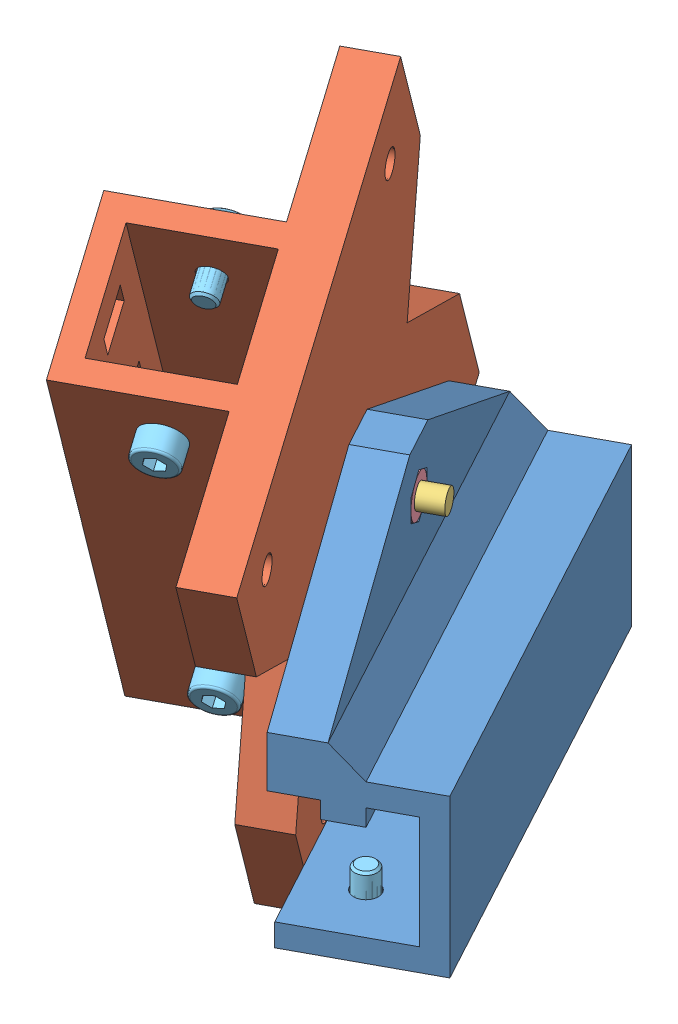
SolidWorks assembly hinge, configuration SymétrieDéfaut. Lengths in mm.
17 component instances, 6 part files, 71 mates.
Components (placement in the parent):
- FoldarapM_hinge-inner_2off-1: FoldarapM_hinge-inner_2off [SymétrieDéfaut] at (2.8366 41.2656 -46.9992) x (0.475399 0 0.87977) z (-0.87977 0 0.475399) size (80 53 24)
- FoldarapM_hinge-outer_2off-1: FoldarapM_hinge-outer_2off [SymétrieDéfaut] at (-8.7977 44 4.754) x (0.428728 -0.432097 0.793401) z (-0.87977 0 0.475399) size (80 80 32)
- Aluminium Profile with 6mm Slot 400mm-1: Aluminium Profile with 6mm Slot 400mm [SymétrieDefault] at (45.704 374.9337 137.2278) x (-0.428728 0.432097 -0.793401) z (-0.205419 -0.901827 -0.380146) size (20 20 400)
- slotted cheese head screw_din-1: slotted cheese head screw_din [PreviewCfg] at (-14.6042 44 7.8916) x (0.87977 0 -0.475399) z (-0.475399 0 -0.87977) size (18.61 7 7)
- hex nut style 1 gradeab_din-1: hex nut style 1 gradeab_din [PreviewCfg] at (-4.5748 44 2.4721) x (-0.475399 0 -0.87977) z (-0.87977 0 0.475399) size (8 9.24 4.7)
- socket head cap screw_din2-1: socket head cap screw_din2 [DIN 912 M4 x 8 --- 8C] at (14.262 -4 26.3931) x (0 1 0) z (0.546944 0 -0.837169) size (12 7 7)
- socket head cap screw_din2-2: socket head cap screw_din2 [DIN 912 M4 x 8 --- 8C] at (0 -4 0) x (0 1 0) z (0.546944 0 -0.837169) size (12 7 7)
- socket head cap screw_din2-3: socket head cap screw_din2 [DIN 912 M4 x 8 --- 8C] at (-14.262 -4 -26.3931) x (0 1 0) z (0.546944 0 -0.837169) size (12 7 7)
- socket head cap screw_din2-4: socket head cap screw_din2 [DIN 912 M4 x 8 --- 8C] at (-46.632 16.9452 10.464) x (0.87977 0 -0.475399) z (0.475399 0 0.87977) size (12 7 7)
- socket head cap screw_din2-5: socket head cap screw_din2 [DIN 912 M4 x 8 --- 8C] at (-26.1881 78.8326 10.4344) x (0.428728 -0.432097 0.793401) z (-0.812844 0.198803 0.547505) size (12 7 7)
- socket head cap screw_din2-6: socket head cap screw_din2 [DIN 912 M4 x 8 --- 8C] at (-38.5132 24.7229 -12.3744) x (0.428728 -0.432097 0.793401) z (-0.812844 0.198803 0.547505) size (12 7 7)
- socket head cap screw_din2-7: socket head cap screw_din2 [DIN 912 M4 x 8 --- 8C] at (-23.079 9.1674 16.188) x (-0.428728 0.432097 -0.793401) z (-0.812844 0.198803 0.547505) size (12 7 7)
- socket head cap screw_din2-8: socket head cap screw_din2 [DIN 912 M4 x 8 --- 8C] at (-10.7539 63.2771 38.9968) x (-0.428728 0.432097 -0.793401) z (-0.812844 0.198803 0.547505) size (12 7 7)
- socket head cap screw_din2-9: socket head cap screw_din2 [DIN 912 M4 x 8 --- 8N] at (-26.0542 84.0177 -1.9388) x (0.87977 0 -0.475399) z (0.475399 0 0.87977) size (12 7 7)
- socket head cap screw_din2-10: socket head cap screw_din2 [DIN 912 M4 x 8 --- 8N] at (-38.3793 29.9081 -24.7476) x (0.87977 0 -0.475399) z (0.475399 0 0.87977) size (12 7 7)
- socket head cap screw_din2-11: socket head cap screw_din2 [DIN 912 M4 x 8 --- 8N] at (-12.6557 3.9823 22.8564) x (0.87977 0 -0.475399) z (0.475399 0 0.87977) size (12 7 7)
- socket head cap screw_din2-12: socket head cap screw_din2 [DIN 912 M4 x 8 --- 8N] at (-0.3305 58.0919 45.6652) x (0.87977 0 -0.475399) z (0.475399 0 0.87977) size (12 7 7)
Mates (geometry in assembly coordinates):
- Coaxiale1: concentric aligned: cylinder of FoldarapM_hinge-inner_2off-1 through (-1.7595 44 0.9508) axis (0.87977 0 -0.475399) radius 2.25; cylinder of FoldarapM_hinge-outer_2off-1 through (-8.7977 44 4.754) axis (0.87977 0 -0.475399) radius 2.2
- Coïncidente1: coincident anti-aligned: plane of FoldarapM_hinge-inner_2off-1 through (10.2183 24 39.9448) normal (-0.87977 0 0.475399); plane of FoldarapM_hinge-outer_2off-1 through (-8.7977 44 4.754) normal (0.87977 0 -0.475399)
- Coaxiale2: concentric anti-aligned: cylinder of FoldarapM_hinge-outer_2off-1 through (-8.7977 44 4.754) axis (0.87977 0 -0.475399) radius 2.2; cylinder of slotted cheese head screw_din-1 through (-36.9503 44 19.9668) axis (-0.87977 0 0.475399) radius 2
- Coïncidente2: coincident anti-aligned: plane of FoldarapM_hinge-outer_2off-1 through (-12.3168 44 6.6556) normal (-0.87977 0 0.475399); plane of slotted cheese head screw_din-1 through (-12.3168 42 6.6556) normal (0.87977 0 -0.475399)
- Coaxiale3: concentric aligned: cylinder of slotted cheese head screw_din-1 through (-36.9503 44 19.9668) axis (-0.87977 0 0.475399) radius 2; cylinder of hex nut style 1 gradeab_din-1 through (17.4524 44 -9.4307) axis (-0.87977 0 0.475399) radius 2
- Coïncidente3: coincident aligned: plane of FoldarapM_hinge-outer_2off-1; plane of Aluminium Profile with 6mm Slot 400mm-1
- Coïncidente4: coincident anti-aligned: plane of FoldarapM_hinge-outer_2off-1 through (-31.6289 2.9436 21.4006) normal (0.87977 0 -0.475399); plane of Aluminium Profile with 6mm Slot 400mm-1 through (-25.7345 7.2886 32.3087) normal (-0.87977 0 0.475399)
- Coïncidente5: coincident anti-aligned: plane of FoldarapM_hinge-outer_2off-1; plane of Aluminium Profile with 6mm Slot 400mm-1
- Coïncidente6: coincident aligned: plane of FoldarapM_hinge-inner_2off-1 through (17.2564 53 36.1416) normal (0.87977 0 -0.475399); plane of hex nut style 1 gradeab_din-1 through (-1.7595 39.9585 0.9508) normal (0.87977 0 -0.475399)
- Parallèle1: parallel anti-aligned: plane of FoldarapM_hinge-inner_2off-1 through (31.3328 0 28.5352) normal (0 -1 0); plane of assembly through (0 0 0) normal (0 1 0)
- Coïncidente8: coincident: line of FoldarapM_hinge-inner_2off-1 through (19.016 0 35.1908) axis (-0.475399 0 -0.87977); point of assembly
- Coïncidente9: coincident: line of FoldarapM_hinge-inner_2off-1 through (-7.9179 0 4.2786) axis (0.87977 0 -0.475399); point of assembly
- Coaxiale4: concentric aligned: cylinder of FoldarapM_hinge-inner_2off-1 through (14.262 0 26.3931) axis (0 -1 0) radius 2.2; cylinder of socket head cap screw_din2-1 through (14.262 -35.75 26.3931) axis (0 -1 0) radius 3.5
- Coïncidente10: coincident anti-aligned: plane of FoldarapM_hinge-inner_2off-1 through (31.3328 0 28.5352) normal (0 -1 0); plane of socket head cap screw_din2-1 through (17.1921 0 28.3074) normal (0 1 0)
- Coaxiale5: concentric aligned: cylinder of FoldarapM_hinge-inner_2off-1 through (0 0 0) axis (0 -1 0) radius 2.2; cylinder of socket head cap screw_din2-2 through (0 -35.75 0) axis (0 -1 0) radius 3.5
- Coïncidente11: coincident anti-aligned: plane of FoldarapM_hinge-inner_2off-1 through (31.3328 0 28.5352) normal (0 -1 0); plane of socket head cap screw_din2-2 through (2.9301 0 1.9143) normal (0 1 0)
- Coaxiale6: concentric aligned: cylinder of FoldarapM_hinge-inner_2off-1 through (-14.262 0 -26.3931) axis (0 -1 0) radius 2.2; cylinder of socket head cap screw_din2-3 through (-14.262 -35.75 -26.3931) axis (0 -1 0) radius 3.5
- Coïncidente12: coincident anti-aligned: plane of FoldarapM_hinge-inner_2off-1 through (31.3328 0 28.5352) normal (0 -1 0); plane of socket head cap screw_din2-3 through (-11.3319 0 -24.4788) normal (0 1 0)
- Coaxiale7: concentric aligned: cylinder of FoldarapM_hinge-outer_2off-1 through (-32.2337 15.6881 28.6954) axis (-0.87977 0 0.475399) radius 2.2; cylinder of socket head cap screw_din2-4 through (-63.6855 15.6881 45.6909) axis (-0.87977 0 0.475399) radius 3.5
- Coïncidente13: coincident anti-aligned: plane of FoldarapM_hinge-outer_2off-1 through (-36.9426 1.6208 19.9812) normal (-0.87977 0 0.475399); plane of socket head cap screw_din2-4 through (-32.2337 19.1881 28.6954) normal (0.87977 0 -0.475399)
- Coaxiale8: concentric anti-aligned: cylinder of FoldarapM_hinge-outer_2off-1 through (-23.0691 76.9419 16.2063) axis (0.448649 0.330715 0.830266) radius 2.2; cylinder of socket head cap screw_din2-5 through (-51.6705 55.8589 -36.7231) axis (-0.448649 -0.330715 -0.830266) radius 3.5
- Coïncidente14: coincident anti-aligned: plane of FoldarapM_hinge-outer_2off-1; plane of socket head cap screw_din2-5
- Coaxiale9: concentric anti-aligned: cylinder of FoldarapM_hinge-outer_2off-1 through (-13.6358 20.3181 33.6635) axis (0.448649 0.330715 0.830266) radius 2.2; cylinder of socket head cap screw_din2-6 through (-42.2372 -0.765 -19.266) axis (-0.448649 -0.330715 -0.830266) radius 3.5
- Coïncidente15: coincident anti-aligned: plane of FoldarapM_hinge-outer_2off-1; plane of socket head cap screw_din2-6
- Coaxiale10: concentric aligned: cylinder of FoldarapM_hinge-outer_2off-1 through (-13.6358 20.3181 33.6635) axis (0.448649 0.330715 0.830266) radius 2.2; cylinder of socket head cap screw_din2-7 through (2.4034 32.1411 63.3455) axis (0.448649 0.330715 0.830266) radius 3.5
- Coïncidente16: coincident anti-aligned: plane of FoldarapM_hinge-outer_2off-1; plane of socket head cap screw_din2-7
- Coaxiale11: concentric aligned: cylinder of FoldarapM_hinge-outer_2off-1 through (-23.0691 76.9419 16.2063) axis (0.448649 0.330715 0.830266) radius 2.2; cylinder of socket head cap screw_din2-8 through (-7.0299 88.765 45.8883) axis (0.448649 0.330715 0.830266) radius 3.5
- Coïncidente17: coincident anti-aligned: plane of FoldarapM_hinge-outer_2off-1; plane of socket head cap screw_din2-8
- Coaxiale12: concentric anti-aligned: cylinder of FoldarapM_hinge-outer_2off-1 through (-26.9738 62.3905 -28.8826) axis (0.87977 0 -0.475399) radius 2.2; cylinder of socket head cap screw_din2-9 through (-65.4638 62.3905 -8.0839) axis (-0.87977 0 0.475399) radius 3.5
- Coïncidente18: coincident anti-aligned: plane of FoldarapM_hinge-outer_2off-1 through (-15.8359 44 8.5572) normal (-0.87977 0 0.475399); plane of socket head cap screw_din2-9 through (-34.012 65.8905 -25.0794) normal (0.87977 0 -0.475399)
- Coaxiale13: concentric anti-aligned: cylinder of FoldarapM_hinge-outer_2off-1 through (-17.5405 5.7666 -11.4254) axis (0.87977 0 -0.475399) radius 2.2; cylinder of socket head cap screw_din2-10 through (-56.0305 5.7666 9.3733) axis (-0.87977 0 0.475399) radius 3.5
- Coïncidente19: coincident anti-aligned: plane of FoldarapM_hinge-outer_2off-1 through (-15.8359 44 8.5572) normal (-0.87977 0 0.475399); plane of socket head cap screw_din2-10 through (-24.5787 9.2666 -7.6222) normal (0.87977 0 -0.475399)
- Coaxiale14: concentric anti-aligned: cylinder of FoldarapM_hinge-outer_2off-1 through (9.3784 25.6095 38.3906) axis (0.87977 0 -0.475399) radius 2.2; cylinder of socket head cap screw_din2-11 through (-29.1115 25.6095 59.1893) axis (-0.87977 0 0.475399) radius 3.5
- Coïncidente20: coincident anti-aligned: plane of FoldarapM_hinge-outer_2off-1 through (-15.8359 44 8.5572) normal (-0.87977 0 0.475399); plane of socket head cap screw_din2-11 through (2.3403 29.1095 42.1938) normal (0.87977 0 -0.475399)
- Coaxiale15: concentric anti-aligned: cylinder of FoldarapM_hinge-outer_2off-1 through (-0.0549 82.2334 20.9334) axis (0.87977 0 -0.475399) radius 2.2; cylinder of socket head cap screw_din2-12 through (-38.5448 82.2334 41.7321) axis (-0.87977 0 0.475399) radius 3.5
- Coïncidente21: coincident anti-aligned: plane of FoldarapM_hinge-outer_2off-1 through (-15.8359 44 8.5572) normal (-0.87977 0 0.475399); plane of socket head cap screw_din2-12 through (-7.093 85.7334 24.7366) normal (0.87977 0 -0.475399)
- Coaxiale16: concentric aligned: cylinder of FoldarapM_hinge-inner_2off-1 through (-1.7595 44 -0.9508) axis (0.87977 0 0.475399) radius 2.25; cylinder of FoldarapM_hinge-outer_2off-1 through (-8.7977 44 -4.754) axis (0.87977 0 0.475399) radius 2.2
- Coïncidente22: coincident anti-aligned: plane of FoldarapM_hinge-inner_2off-1 through (10.2183 24 -39.9448) normal (-0.87977 0 -0.475399); plane of FoldarapM_hinge-outer_2off-1 through (-8.7977 44 -4.754) normal (0.87977 0 0.475399)
- Coaxiale17: concentric anti-aligned: cylinder of FoldarapM_hinge-outer_2off-1 through (-8.7977 44 -4.754) axis (0.87977 0 0.475399) radius 2.2; cylinder of slotted cheese head screw_din-1 through (-36.9503 44 -19.9668) axis (-0.87977 0 -0.475399) radius 2
- Coïncidente23: coincident anti-aligned: plane of FoldarapM_hinge-outer_2off-1 through (-12.3168 44 -6.6556) normal (-0.87977 0 -0.475399); plane of slotted cheese head screw_din-1 through (-12.3168 42 -6.6556) normal (0.87977 0 0.475399)
- Coaxiale18: concentric aligned: cylinder of slotted cheese head screw_din-1 through (-36.9503 44 -19.9668) axis (-0.87977 0 -0.475399) radius 2; cylinder of hex nut style 1 gradeab_din-1 through (17.4524 44 9.4307) axis (-0.87977 0 -0.475399) radius 2
- Coïncidente24: coincident aligned: plane of FoldarapM_hinge-outer_2off-1 through (-42.7284 44.1604 41.2099) normal (-0.33711 -0.705099 0.623853); plane of Aluminium Profile with 6mm Slot 400mm-1 through (-38.539 22.5269 19.0229) normal (-0.33711 -0.705099 0.623853)
- Coïncidente25: coincident anti-aligned: plane of FoldarapM_hinge-outer_2off-1 through (-50.2677 22.8871 13.0922) normal (0.87977 0 0.475399); plane of Aluminium Profile with 6mm Slot 400mm-1 through (-45.8638 13.5708 4.9423) normal (-0.87977 0 -0.475399)
- Coïncidente26: coincident anti-aligned: plane of FoldarapM_hinge-outer_2off-1 through (-32.6723 22.8871 22.6002) normal (0.335204 -0.709109 -0.620325); plane of Aluminium Profile with 6mm Slot 400mm-1 through (-38.7093 22.8871 19.338) normal (-0.335204 0.709109 0.620325)
- Coïncidente27: coincident aligned: plane of FoldarapM_hinge-inner_2off-1 through (17.2564 53 -36.1416) normal (0.87977 0 0.475399); plane of hex nut style 1 gradeab_din-1 through (-1.7595 39.9585 -0.9508) normal (0.87977 0 0.475399)
- Parallèle2: parallel anti-aligned: plane of FoldarapM_hinge-inner_2off-1 through (31.3328 0 -28.5352) normal (0 -1 0); plane of assembly through (0 0 0) normal (0 1 0)
- Coïncidente28: coincident: line of ? through (51.6231 0 27.8955) axis (-0.87977 0 -0.475399)
- Coaxiale19: concentric aligned: cylinder of FoldarapM_hinge-inner_2off-1 through (14.262 0 -26.3931) axis (0 -1 0) radius 2.2; cylinder of socket head cap screw_din2-1 through (14.262 -35.75 -26.3931) axis (0 -1 0) radius 3.5
- Coïncidente29: coincident anti-aligned: plane of FoldarapM_hinge-inner_2off-1 through (31.3328 0 -28.5352) normal (0 -1 0); plane of socket head cap screw_din2-1 through (17.1921 0 -28.3074) normal (0 1 0)
- Coaxiale20: concentric aligned: cylinder of FoldarapM_hinge-inner_2off-1 through (0 0 0) axis (0 -1 0) radius 2.2; cylinder of socket head cap screw_din2-2 through (0 -35.75 0) axis (0 -1 0) radius 3.5
- Coïncidente30: coincident anti-aligned: plane of FoldarapM_hinge-inner_2off-1 through (31.3328 0 -28.5352) normal (0 -1 0); plane of socket head cap screw_din2-2 through (2.9301 0 -1.9143) normal (0 1 0)
- Coaxiale21: concentric aligned: cylinder of FoldarapM_hinge-inner_2off-1 through (-14.262 0 26.3931) axis (0 -1 0) radius 2.2; cylinder of socket head cap screw_din2-3 through (-14.262 -35.75 26.3931) axis (0 -1 0) radius 3.5
- Coïncidente31: coincident anti-aligned: plane of FoldarapM_hinge-inner_2off-1 through (31.3328 0 -28.5352) normal (0 -1 0); plane of socket head cap screw_din2-3 through (-11.3319 0 24.4788) normal (0 1 0)
- Coaxiale22: concentric aligned: cylinder of FoldarapM_hinge-outer_2off-1 through (-47.0636 22.847 -1.2512) axis (-0.87977 0 -0.475399) radius 2.2; cylinder of socket head cap screw_din2-4 through (-78.5154 22.847 -18.2467) axis (-0.87977 0 -0.475399) radius 3.5
- Coïncidente32: coincident anti-aligned: plane of FoldarapM_hinge-outer_2off-1 through (-55.1276 25.7235 13.6719) normal (-0.87977 0 -0.475399); plane of socket head cap screw_din2-4 through (-47.0636 26.347 -1.2512) normal (0.87977 0 0.475399)
- Coaxiale23: concentric anti-aligned: cylinder of FoldarapM_hinge-outer_2off-1 through (-9.8274 55.2255 -40.7113) axis (0.335204 -0.709109 -0.620325) radius 2.2; cylinder of socket head cap screw_din2-5 through (-31.1967 100.4311 -1.1656) axis (-0.335204 0.709109 0.620325) radius 3.5
- Coïncidente33: coincident anti-aligned: plane of FoldarapM_hinge-outer_2off-1 through (-30.494 25.7235 26.9831) normal (-0.335204 0.709109 0.620325); plane of socket head cap screw_din2-5 through (-17.3835 77.4876 -25.1052) normal (0.335204 -0.709109 -0.620325)
- Coaxiale24: concentric anti-aligned: cylinder of FoldarapM_hinge-outer_2off-1 through (-30.054 12.9195 -3.2802) axis (0.335204 -0.709109 -0.620325) radius 2.2; cylinder of socket head cap screw_din2-6 through (-51.4232 58.1252 36.2656) axis (-0.335204 0.709109 0.620325) radius 3.5
- Coïncidente34: coincident anti-aligned: plane of FoldarapM_hinge-outer_2off-1 through (-30.494 25.7235 26.9831) normal (-0.335204 0.709109 0.620325); plane of socket head cap screw_din2-6 through (-37.6101 35.1817 12.326) normal (0.335204 -0.709109 -0.620325)
- Coaxiale25: concentric aligned: cylinder of FoldarapM_hinge-outer_2off-1 through (-30.054 12.9195 -3.2802) axis (0.335204 -0.709109 -0.620325) radius 2.2; cylinder of socket head cap screw_din2-7 through (-18.0705 -12.4311 -25.4568) axis (0.335204 -0.709109 -0.620325) radius 3.5
- Coïncidente35: coincident anti-aligned: plane of FoldarapM_hinge-outer_2off-1 through (-21.1083 5.8685 9.614) normal (0.335204 -0.709109 -0.620325); plane of socket head cap screw_din2-7 through (-31.8837 10.5124 -1.5172) normal (-0.335204 0.709109 0.620325)
- Coaxiale26: concentric aligned: cylinder of FoldarapM_hinge-outer_2off-1 through (-9.8274 55.2255 -40.7113) axis (0.335204 -0.709109 -0.620325) radius 2.2; cylinder of socket head cap screw_din2-8 through (2.1561 29.8748 -62.8879) axis (0.335204 -0.709109 -0.620325) radius 3.5
- Coïncidente36: coincident anti-aligned: plane of FoldarapM_hinge-outer_2off-1 through (-21.1083 5.8685 9.614) normal (0.335204 -0.709109 -0.620325); plane of socket head cap screw_din2-8 through (-11.6571 52.8183 -38.9483) normal (-0.335204 0.709109 0.620325)
- Coaxiale27: concentric anti-aligned: cylinder of FoldarapM_hinge-outer_2off-1 through (-8.7405 86.4262 -4.8598) axis (0.87977 0 0.475399) radius 2.2; cylinder of socket head cap screw_din2-9 through (-47.2305 86.4262 -25.6585) axis (-0.87977 0 -0.475399) radius 3.5
- Coïncidente37: coincident anti-aligned: plane of FoldarapM_hinge-outer_2off-1 through (-15.8359 44 -8.5572) normal (-0.87977 0 -0.475399); plane of socket head cap screw_din2-9 through (-15.7787 89.9262 -8.663) normal (0.87977 0 0.475399)
- Coaxiale28: concentric anti-aligned: cylinder of FoldarapM_hinge-outer_2off-1 through (-28.9671 44.1203 32.5713) axis (0.87977 0 0.475399) radius 2.2; cylinder of socket head cap screw_din2-10 through (-67.457 44.1203 11.7726) axis (-0.87977 0 -0.475399) radius 3.5
- Coïncidente38: coincident anti-aligned: plane of FoldarapM_hinge-outer_2off-1 through (-15.8359 44 -8.5572) normal (-0.87977 0 -0.475399); plane of socket head cap screw_din2-10 through (-36.0053 47.6203 28.7681) normal (0.87977 0 0.475399)
- Coaxiale29: concentric anti-aligned: cylinder of FoldarapM_hinge-outer_2off-1 through (-8.8549 1.5738 -4.6482) axis (0.87977 0 0.475399) radius 2.2; cylinder of socket head cap screw_din2-11 through (-47.3448 1.5738 -25.4469) axis (-0.87977 0 -0.475399) radius 3.5
- Coïncidente39: coincident anti-aligned: plane of FoldarapM_hinge-outer_2off-1 through (-15.8359 44 -8.5572) normal (-0.87977 0 -0.475399); plane of socket head cap screw_din2-11 through (-15.893 5.0738 -8.4514) normal (0.87977 0 0.475399)
- Coaxiale30: concentric anti-aligned: cylinder of FoldarapM_hinge-outer_2off-1 through (11.3717 43.8797 -42.0793) axis (0.87977 0 0.475399) radius 2.2; cylinder of socket head cap screw_din2-12 through (-27.1182 43.8797 -62.878) axis (-0.87977 0 -0.475399) radius 3.5
- Coïncidente40: coincident anti-aligned: plane of FoldarapM_hinge-outer_2off-1 through (-15.8359 44 -8.5572) normal (-0.87977 0 -0.475399); plane of socket head cap screw_din2-12 through (4.3335 47.3797 -45.8825) normal (0.87977 0 0.475399)
